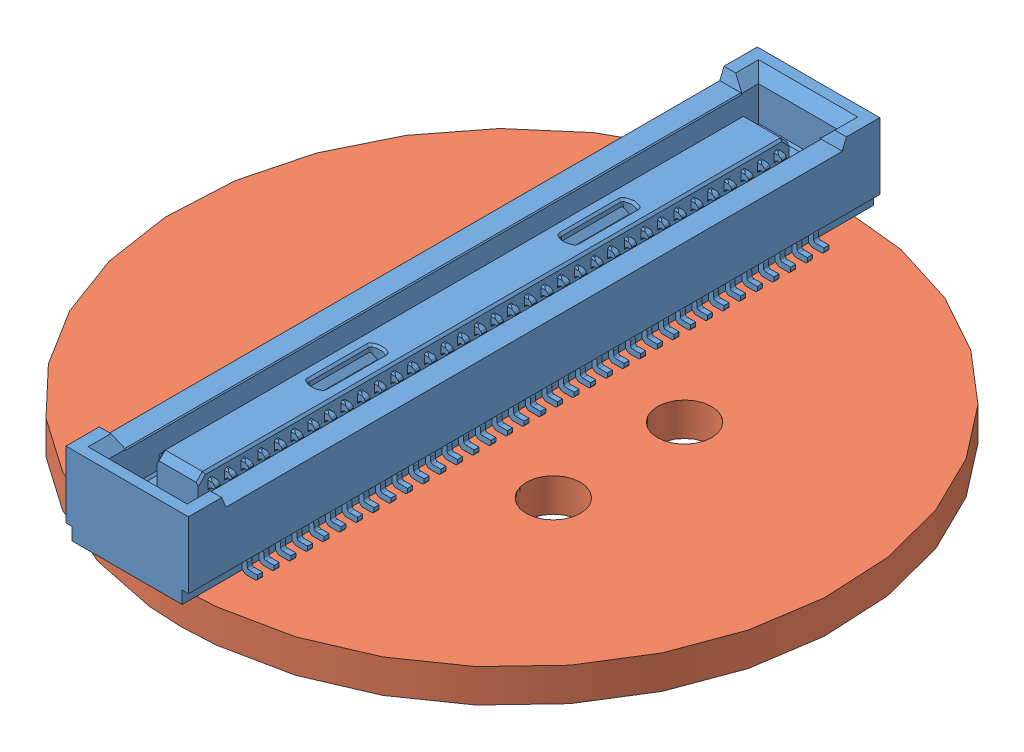
SolidWorks assembly EIB_w_hirose, configuration Default. Lengths in mm.
Overall size (15.85 2.75 16.6).
2 component instances, 2 part files, 6 mates.
Components (placement in the parent):
- DF40C(2.0)-70DS.stp-1: DF40C(2.0)-70DS.stp [Default] at (-0.925 1.35 3.115) size (3.38 1.95 16.6)
- EIB_PCB-1: EIB_PCB [Default] at origin size (15.85 0.8 16.6)
Mates (geometry in assembly coordinates):
- Coincident1: coincident aligned: plane of EIB_PCB-1 through (0 0 0) normal (0 1 0)
- Coincident2: coincident aligned: plane of EIB_PCB-1 through (0 0 0) normal (0 0 1)
- Coincident3: coincident aligned: plane of EIB_PCB-1 through (0 0 0) normal (1 0 0)
- Coincident5: coincident anti-aligned: plane of DF40C(2.0)-70DS.stp-1 through (0.465 0.8 6.86) normal (0 -1 0); plane of EIB_PCB-1 through (0 0.8 0) normal (0 1 0)
- Symmetric1: symmetric aligned: plane of DF40C(2.0)-70DS.stp-1 through (-1.5952 1.638 8.3) normal (0 0 1); plane of DF40C(2.0)-70DS.stp-1 through (-1.5952 1.638 -8.3) normal (0 0 -1)
- Coincident6: coincident: plane of DF40C(2.0)-70DS.stp-1 through (-0.925 1.35 3.115) normal (1 0 0); line of EIB_PCB-1 through (-0.925 0.8 -8.3) axis (0 0 1)
